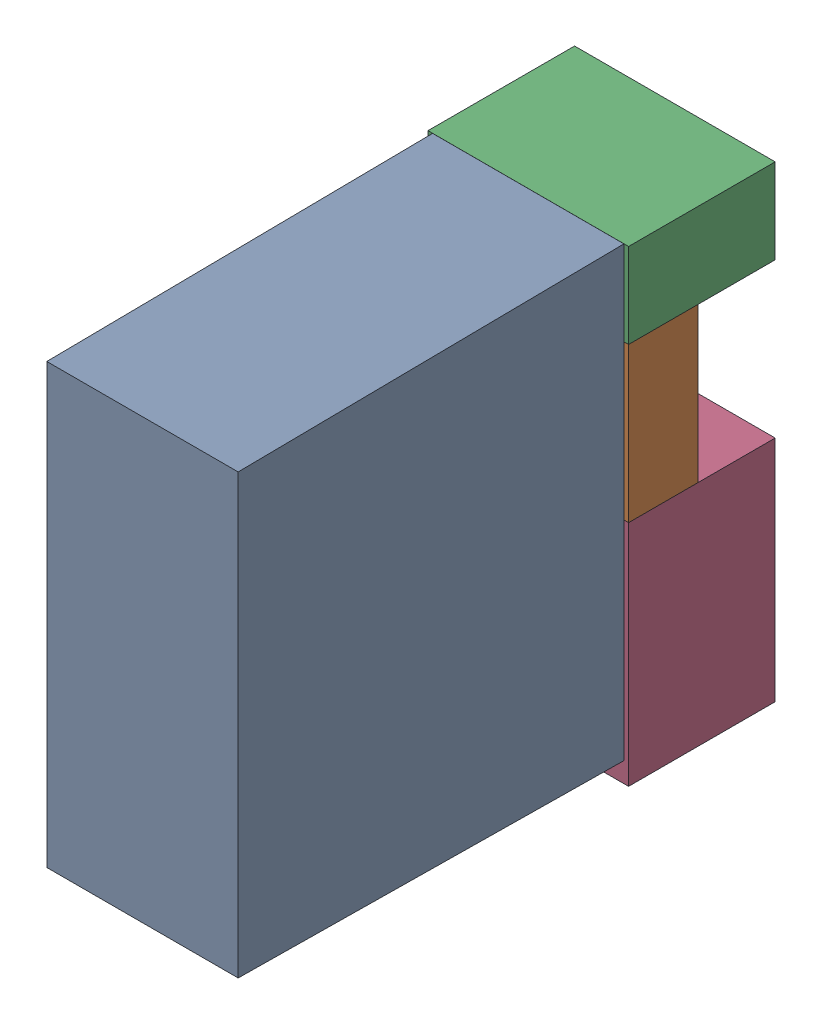
SolidWorks assembly K5, configuration Default. Lengths in mm.
Overall size (13 30.3 34.5).
7 component instances, 4 part files, 0 mates.
Components (placement in the parent):
- relais_40_61_8_006_0000-1: relais_40_61_8_006_0000 [Default] at (67.945 15.7216 9.5) x (0 1 0) z (1 0 0) size (29 30 12.4)
- 1151725064-1: 1151725064 [Default] at (67.945 34.225 5) size (13 10 4.5)
  - Extruded_3-1: Extruded_3 [Default] at origin size (13 10 4.5)
- 1151724928-1: 1151724928 [Default] at (67.945 41.975 0) size (13 5.5 9.5)
  - Extruded_2-1: Extruded_2 [Default] at origin size (13 5.5 9.5)
- 1151724792-1: 1151724792 [Default] at (67.945 21.825 0) size (13 14.8 9.5)
  - Extruded_4-1: Extruded_4 [Default] at origin size (13 14.8 9.5)
